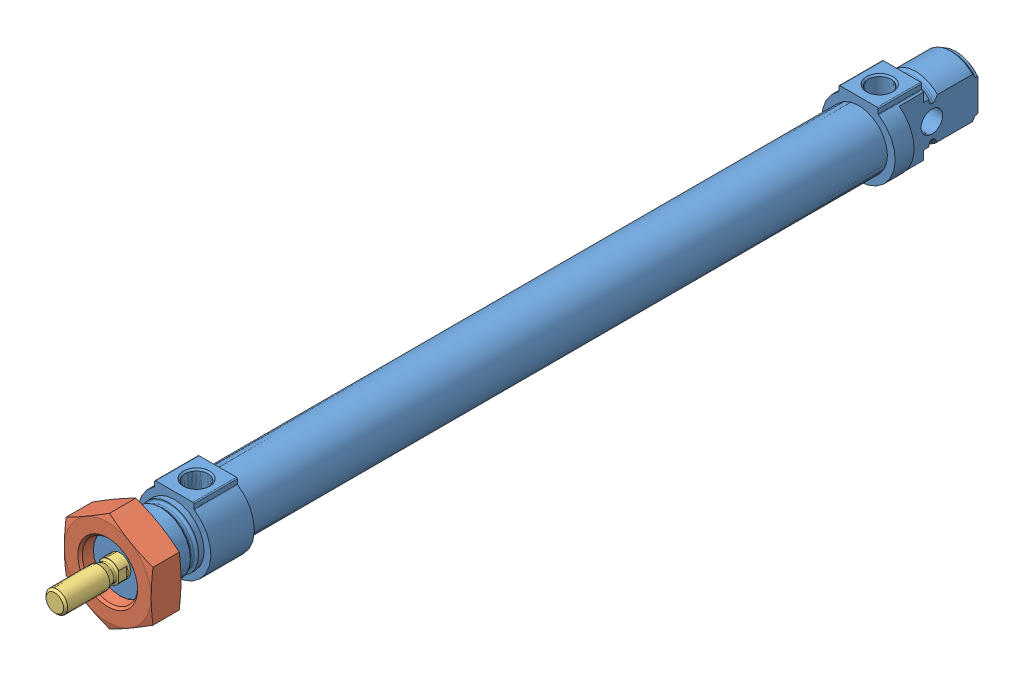
SolidWorks assembly Baugruppe127, configuration Standard. Lengths in mm.
Overall size (32 36.95 332).
3 component instances, 3 part files, 3 mates.
Components (placement in the parent):
- 559278_DSNU_20_200_PPS____A____0_ZR_-1: 559278_DSNU_20_200_PPS____A____0_ZR_ [Standard] x (0 0 -1) z (1 0 0) size (308 27 27)
- DIN_439_B___M22x1_5_F_-1: DIN_439_B___M22x1_5_F_ [Standard] at (0 0 4.5) x (-1 0 0) z (0 1 0) size (32 11 36.95)
- 559278_DSNU_20_200_PPS____A___00__0_KS_-1: 559278_DSNU_20_200_PPS____A___00__0_KS_ [Standard] x (-1 0 0) z (0 0 1) size (20 20 279.3)
Mates (geometry in assembly coordinates):
- Abstand3: distance = 5.5 mm anti-aligned: plane of DIN_439_B___M22x1_5_F_-1; plane of 559278_DSNU_20_200_PPS____A____0_ZR_-1 through (0 0 -6.5) normal (0 0 -1)
- Deckungsgleich1: coincident anti-aligned: line of 559278_DSNU_20_200_PPS____A____0_ZR_-1 through (0 0 -80.9) axis (0 0 1); line of DIN_439_B___M22x1_5_F_-1 through (0 0 54.5) axis (0 0 -1)
- Winkel3: planar angle = 0 rad aligned: plane of DIN_439_B___M22x1_5_F_-1; plane of 559278_DSNU_20_200_PPS____A____0_ZR_-1 through (0 0 0) normal (-1 0 0)
